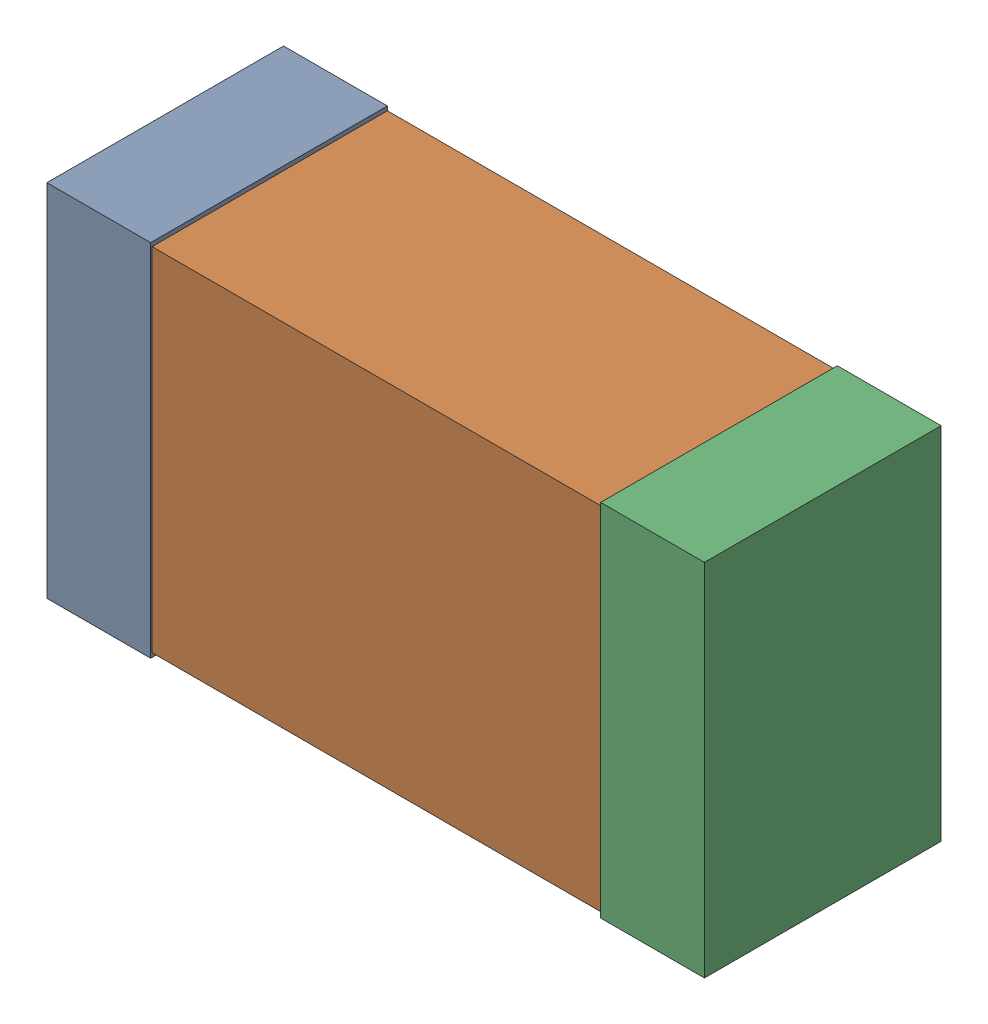
SolidWorks assembly C9_Motor_9Kanaloa_v2.0.0_Motor, configuration Default. Lengths in mm.
Overall size (2.38 1.3 0.85).
6 component instances, 2 part files, 0 mates.
Components (placement in the parent):
- 352877648-1: 352877648 [Default] at (33.95 161.036 0) size (0.38 1.3 0.85)
  - Extruded_14-1: Extruded_14 [Default] at origin size (0.38 1.3 0.85)
- 352877392-1: 352877392 [Default] at (34.95 161.036 0) size (2.2 1.27 0.85)
  - Extruded_15-1: Extruded_15 [Default] at origin size (2.2 1.27 0.85)
- 352877648-2: 352877648 [Default] at (35.95 161.036 0) size (0.38 1.3 0.85)
  - Extruded_14-1: Extruded_14 [Default] at origin size (0.38 1.3 0.85)
